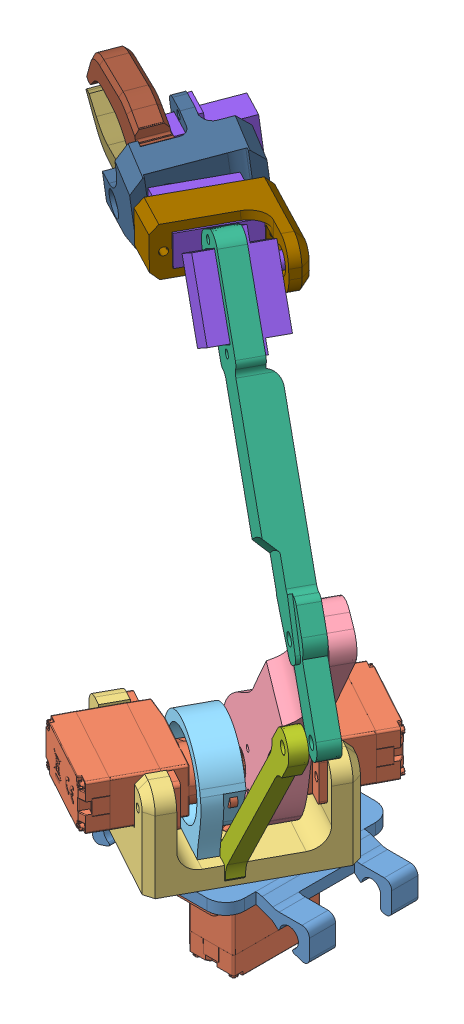
SolidWorks assembly 机械臂, configuration 默认. Lengths in mm.
Overall size (125.83 175.27 83.41).
17 component instances, 12 part files, 34 mates.
Components (placement in the parent):
- 顶盖 2个 机械臂-1: 顶盖 2个 机械臂 [Default] at (-5.0565 2.4171 58) size (58 10.04 45)
- 舵机9g-1: 舵机9g [Default] at (-11.3737 -13.5847 69.5895) size (24 29.92 33.96)
- 旋转底座-1: 旋转底座 [默认] at (-14.4585 10.4671 61.5154) x (0.479503 0 -0.87754) z (0 -1 0) size (43 38.46 24.15)
- 舵机9g-2: 舵机9g [Default] at (12.3354 17.5534 45.2411) x (-0.000001 1 0) z (0.87754 0.000001 0.479503) size (24 29.92 33.96)
- 舵机9g-3: 舵机9g [Default] at (-11.2855 29.8369 88.5306) x (0.000001 -1 0) z (0.87754 0.000001 0.479503) size (24 29.92 33.96)
- 机械臂大-1: 机械臂大 [默认] at (-7.3662 13.3036 61.0864) x (0.479503 0 -0.87754) z (0.711658 -0.585088 0.388862) size (9 87.55 25.1)
- 机械臂小-1: 机械臂小 [默认] at (-5.8807 34.7609 64.8733) x (-0.479503 0 0.87754) z (0.826601 0.335747 0.451669) size (9 36.82 25.1)
- 机械臂2自由-1: 机械臂2自由 [默认] at (-15.9434 149.2152 62.6672) x (0.479503 0 -0.87754) z (-0.719072 -0.573196 -0.392913) size (9 102.91 12.07)
- 机械臂连杆-1: 机械臂连杆 [默认] at (12.6623 -25.0646 90.412) x (0.479503 0 -0.87754) z (0.696029 -0.609014 0.380322) size (4 82.99 7.99)
- 2.4g舵机-1: 2.4g舵机 [默认] at (1.0488 131.7092 74.7667) x (-0.719072 -0.573196 -0.392913) z (0.479503 0 -0.87754) size (7.91 25 19.8)
- 俯仰-1: 俯仰 [默认] at (-17.54 137.037 68.479) x (-0.876546 -0.047593 -0.47896) z (0.041764 -0.998867 0.022821) size (25 27.72 12.41)
- 2.4g舵机-2: 2.4g舵机 [默认] at (-11.3233 142.1918 53.3953) x (0.041764 -0.998867 0.022821) z (-0.876546 -0.047593 -0.47896) size (7.91 25 19.8)
- 爪子-1: 爪子 [默认] at (-52.7396 135.6806 27.104) x (0.472676 0.102608 -0.875242) z (0.876546 0.047593 0.47896) size (29.28 28.31 50.35)
  - 横滚-1: 横滚 [默认] at (-8.0086 -8.3265 23.9745) size (27.28 25.74 21.41)
  - 2.4g舵机-1: 2.4g舵机 [默认] at (4.4614 -5.0075 18.786) x (0 0 1) z (-1 0 0) size (7.91 25 19.8)
  - 爪子1-1: 爪子1 [默认] at (7.4614 -5.2587 19.5969) x (0 0.070677 0.997499) z (-1 0 0) size (40.46 15.35 7)
  - 爪子2-1: 爪子2 [默认] at (-35.5504 7.9523 19.5737) x (0 -0.068682 0.997639) z (1 0 0) size (40.56 14.12 7)
Mates (geometry in assembly coordinates):
- Parallel5: parallel anti-aligned: plane of 顶盖 2个 机械臂-1 through (1.0022 -4.5829 46.0635) normal (-1 0 0); plane of 舵机9g-1 through (0.9459 -15.1829 69.2572) normal (1 0 0)
- Coincident3: coincident anti-aligned: plane of 顶盖 2个 机械臂-1 through (-5.0565 -2.5829 58) normal (0 -1 0); plane of 舵机9g-1 through (-5.0978 -2.5829 44.1831) normal (0 1 0)
- Concentric10: concentric anti-aligned: cylinder of 顶盖 2个 机械臂-1 through (-5.0978 -4.5829 72.3635) axis (0 1 0) radius 1; cylinder of 舵机9g-1 through (-5.0978 -3.3829 72.3635) axis (0 -1 0) radius 1
- Concentric11: concentric aligned: cylinder of 舵机9g-1 through (-5.0978 6.7671 63.8135) axis (0 1 0) radius 9; cylinder of 旋转底座-1 through (-5.0978 5.4671 63.8135) axis (0 1 0) radius 9.05
- Coincident6: coincident: plane of 旋转底座-1 through (13.5314 27.1719 82.6168) normal (0 -1 0); plane of 舵机9g-2 through (-29.3332 27.1719 56.0289) normal (0 1 0)
- Parallel7: parallel: cylinder of 旋转底座-1 through (-7.425 23.5609 87.0422) axis (0.479503 0 -0.87754) radius 1; cylinder of 舵机9g-2 through (9.8779 23.8294 55.5238) axis (0.479503 0 -0.87754) radius 1
- Coincident7: coincident: plane of 旋转底座-1 through (14.5297 30.4671 57.154) normal (-0.479503 0 0.87754); plane of 舵机9g-2 through (9.9811 23.8294 54.6685) normal (0.479503 0 -0.87754)
- Distance1: distance = 0.4773 mm: plane of 舵机9g-2 through (-7.1866 29.373 32.7528) normal (-0.87754 -0.000001 -0.479503); plane of 旋转底座-1 through (-30.5043 17.4609 74.4312) normal (0.87754 0.000001 0.479503)
- Coincident9: coincident anti-aligned: plane of 舵机9g-1 through (-5.0978 8.2671 63.8135) normal (0 1 0); plane of 旋转底座-1 through (-14.4585 8.2671 61.5154) normal (0 -1 0)
- Coincident10: coincident anti-aligned: plane of 旋转底座-1 through (-0.1004 30.4671 83.9285) normal (0.479503 0 -0.87754); plane of 舵机9g-3 through (-4.6234 23.561 81.457) normal (-0.479503 0 0.87754)
- Parallel11: parallel anti-aligned: plane of 旋转底座-1 through (-9.8857 17.4609 36.697) normal (-0.000001 1 0); plane of 舵机9g-3 through (-12.3435 17.5173 89.7737) normal (0.000001 -1 0)
- Concentric17: concentric aligned: cylinder of 旋转底座-1 through (-11.7285 23.5609 35.6901) axis (-0.479503 0 0.87754) radius 1; cylinder of 舵机9g-3 through (-28.9693 23.5609 67.2424) axis (-0.479503 0 0.87754) radius 1
- Concentric19: concentric: cylinder of 旋转底座-1 through (-7.425 23.5609 87.0422) axis (0.479503 0 -0.87754) radius 1; cylinder of 舵机9g-2 through (9.8779 23.8294 55.5238) axis (0.479503 0 -0.87754) radius 1
- Coincident12: coincident anti-aligned: plane of 舵机9g-2 through (-3.2112 23.8294 61.6474) normal (-0.479503 0 0.87754); plane of 机械臂大-1 through (-3.2112 23.8294 61.6474) normal (0.479503 0 -0.87754)
- Concentric20: concentric aligned: cylinder of 舵机9g-2 through (-3.2112 23.8294 61.6474) axis (-0.479503 0 0.87754) radius 2.95; cylinder of 机械臂大-1 through (-3.2112 23.8294 61.6474) axis (-0.479503 0 0.87754) radius 3.3018
- Coincident13: coincident anti-aligned: plane of 舵机9g-3 through (-5.8761 23.561 66.5852) normal (0.479503 0 -0.87754); plane of 机械臂小-1 through (-5.8761 23.561 66.5852) normal (-0.479503 0 0.87754)
- Concentric21: concentric aligned: cylinder of 舵机9g-3 through (-6.5954 23.561 67.9015) axis (0.479503 0 -0.87754) radius 9; cylinder of 机械臂小-1 through (-5.8761 23.561 66.5852) axis (0.479503 0 -0.87754) radius 3.3018
- Concentric22: concentric aligned: cylinder of 机械臂大-1 through (32.0102 80.5972 82.6023) axis (0.479503 0 -0.87754) radius 1.5; cylinder of 机械臂2自由-1 through (29.3729 80.5972 87.4288) axis (0.479503 0 -0.87754) radius 1.5
- Coincident16: coincident anti-aligned: plane of 机械臂小-1 through (-9.8809 -5.6397 67.838) normal (0.479503 0 -0.87754); plane of 机械臂连杆-1 through (38.6511 64.2089 94.3567) normal (-0.479503 0 0.87754)
- Coincident19: coincident anti-aligned: plane of 机械臂大-1 through (50.3536 85.4723 88.6371) normal (-0.479503 0 0.87754); plane of 机械臂2自由-1 through (-4.0367 142.0536 58.9172) normal (0.479503 0 -0.87754)
- Concentric23: concentric anti-aligned: cylinder of 机械臂2自由-1 through (41.351 64.2089 89.4156) axis (0.479503 0 -0.87754) radius 1.5; cylinder of 机械臂连杆-1 through (40.5691 64.2089 90.8466) axis (-0.479503 0 0.87754) radius 1.5
- Concentric24: concentric aligned: circle of 机械臂小-1; circle of 机械臂连杆-1
- Concentric25: concentric aligned: cylinder of 机械臂2自由-1 through (-9.4029 143.765 66.241) axis (0.479503 0 -0.87754) radius 1; cylinder of 2.4g舵机-1 through (-16.5474 143.765 79.3164) axis (0.479503 0 -0.87754) radius 1
- Coincident21: coincident aligned: cylinder of 机械臂2自由-1 through (1.6179 125.8116 72.263) axis (0.479503 0 -0.87754) radius 1; circle of 2.4g舵机-1
- Coincident22: coincident anti-aligned: plane of 机械臂2自由-1 through (-13.0664 149.2152 57.4019) normal (0.479503 0 -0.87754); plane of 2.4g舵机-1 through (13.4465 161.7789 71.889) normal (-0.479503 0 0.87754)
- Coincident28: coincident anti-aligned: plane of 俯仰-1 through (-26.3054 136.5611 63.6894) normal (-0.876546 -0.047593 -0.47896); plane of 2.4g舵机-2 through (-28.9965 166.7803 65.6115) normal (0.876546 0.047593 0.47896)
- Parallel14: parallel: plane of 俯仰-1 through (2.8489 147.0393 9.5214) normal (0.033898 0.395705 0.917752); plane of 2.4g舵机-2
- Coincident30: coincident: circle of 俯仰-1; circle of 2.4g舵机-2
- Concentric27: concentric aligned: cylinder of 2.4g舵机-1 through (1.0202 138.7289 54.5127) axis (-0.479503 0 0.87754) radius 1.9516; cylinder of 俯仰-1 through (1.1401 138.7289 54.2933) axis (-0.479503 0 0.87754) radius 3.1
- Distance3: distance = 1 mm anti-aligned: plane of 俯仰-1 through (4.4828 145.1806 58.6838) normal (-0.479503 0 0.87754); plane of 2.4g舵机-1 through (-5.4206 139.978 54.4119) normal (0.479503 0 -0.87754)
- Coincident32: coincident anti-aligned: plane of 俯仰-1 through (-17.3687 141.7887 46.8149) normal (0.041764 -0.998867 0.022821); plane of 2.4g舵机-2 through (-11.3233 142.1918 53.3953) normal (-0.041764 0.998867 -0.022821)
- Coincident34: coincident anti-aligned: plane of 俯仰-1 through (-26.2395 141.7887 63.0494) normal (0.479503 0 -0.87754); plane of 2.4g舵机-2 through (-31.4227 133.5883 60.2173) normal (-0.479503 0 0.87754)
- Concentric37: concentric aligned: cylinder of 2.4g舵机-2 through (-32.1599 137.396 54.9246) axis (0.876546 0.047593 0.47896) radius 1.9516; cylinder of 爪子-1/横滚-1 through (-32.1599 137.396 54.9246) axis (0.876546 0.047593 0.47896) radius 3.1
- Coincident54: coincident anti-aligned: plane of 2.4g舵机-2 through (-32.1599 137.396 54.9246) normal (-0.876546 -0.047593 -0.47896); plane of 爪子-1/横滚-1 through (-32.1599 137.396 54.9246) normal (0.876546 0.047593 0.47896)
